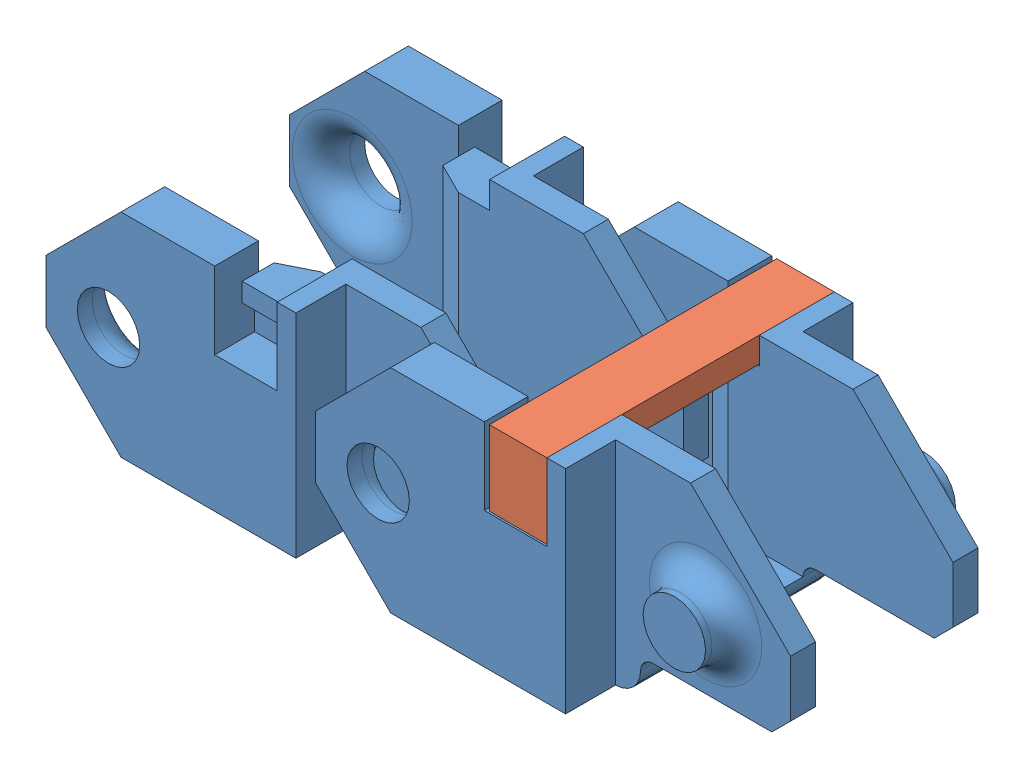
SolidWorks assembly Ensamblaje Eslabon 15, configuration Predeterminado. Lengths in mm.
Overall size (55.58 17 23).
3 component instances, 2 part files, 5 mates.
Components (placement in the parent):
- Eslabon 15-1: Eslabon 15 [Predeterminado] at (-29.411 -6.9992 30.5) size (34 17 23)
- Cierre 15-1: Cierre 15 [Predeterminado] at (-10.911 10.0008 49.5) x (-1 0 0) z (0 0 1) size (4.6 6 23)
- Eslabon 15-2: Eslabon 15 [Predeterminado] at (-50.9902 -6.9992 30.5) size (34 17 23)
Mates (geometry in assembly coordinates):
- Coincidente1: coincident aligned: plane of Eslabon 15-1 through (-29.411 10.0008 30.5) normal (0 1 0); plane of Cierre 15-1 through (-10.911 10.0008 49.5) normal (0 1 0)
- Coincidente2: coincident anti-aligned: plane of Eslabon 15-1 through (-10.911 7.8508 26.5) normal (-1 0 0); plane of Cierre 15-1 through (-10.911 8.0008 49.5) normal (1 0 0)
- Coincidente3: coincident aligned: plane of Eslabon 15-1 through (-29.411 -4.9992 49.5) normal (0 0 1); plane of Cierre 15-1 through (-10.911 8.0008 49.5) normal (0 0 1)
- Coincidente6: coincident aligned: plane of Eslabon 15-1 through (-29.411 10.0008 30.5) normal (0 1 0); plane of Eslabon 15-2 through (-50.9902 10.0008 30.5) normal (0 1 0)
- Distancia1: distance = 0.5 mm anti-aligned: plane of Eslabon 15-2 through (-16.9902 -4.9992 30.5) normal (0 0 -1); plane of Eslabon 15-1 through (-15.911 -18.5084 30) normal (0 0 1)
